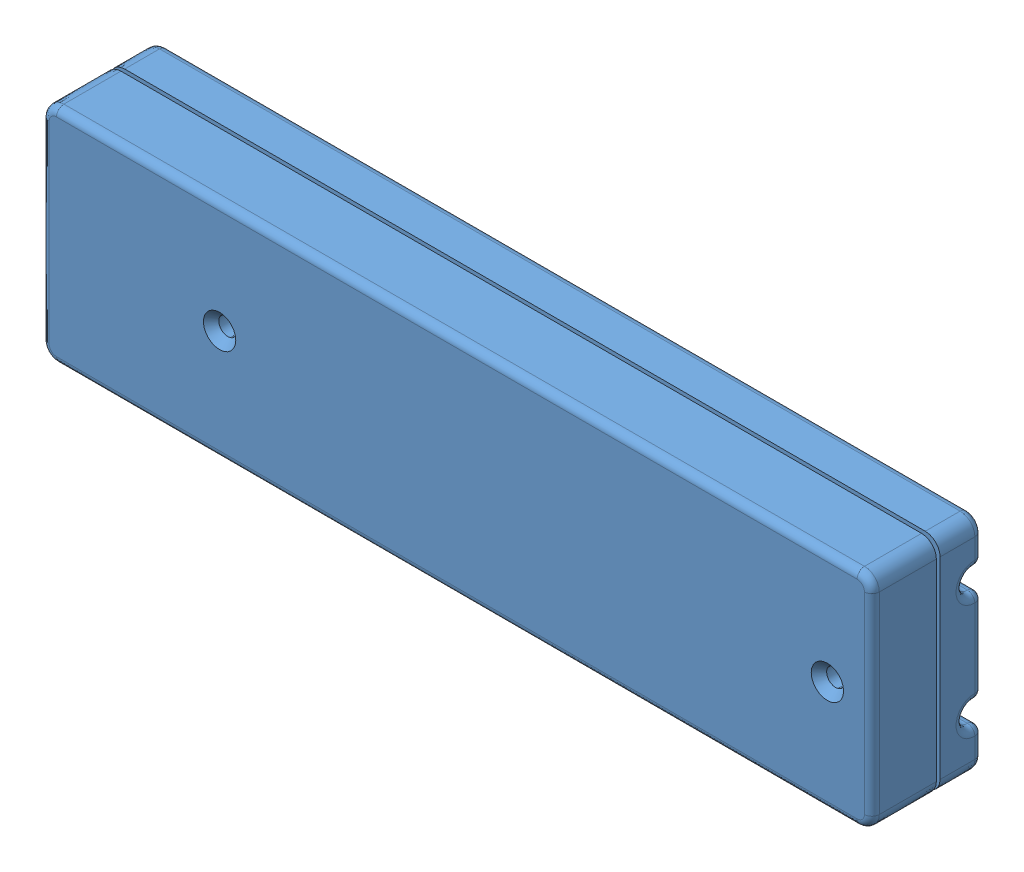
SolidWorks assembly two conector enclosure asm, configuration Default. Lengths in mm.
Overall size (112 30 15.6).
8 component instances, 5 part files, 10 mates.
Components (placement in the parent):
- two conector enclosure-1: two conector enclosure [Default] at origin size (112 30 14.9)
- two connector board asm-1: two connector board asm [Default] at origin size (108.78 25 10.13)
  - board-1: board [Default] at origin size (107 25 1.69)
  - Jack PCB-1: Jack PCB [Default] at (-45.55 -6.925 -3.2) x (-1 0 0) z (0 -1 0) size (19.05 7.4 7.9)
  - Jack PCB-2: Jack PCB [Default] at (-45.55 1.575 -3.2) x (-1 0 0) z (0 -1 0) size (19.05 7.4 7.9)
  - A79623-001-1: A79623-001 [Default] at (-50.96 9.2775 1.692) x (0 -1 0) z (-1 0 0) size (4.45 2.05 6.53)
- wire connector-3: wire connector [Default] at (-35.075 7.7801 0) x (1 0 0) z (0 1 0) size (86.5 9.6 7.28)
- wire connector-4: wire connector [Default] at (-35.075 -7.7801 0) x (1 0 0) z (0 1 0) size (86.5 9.6 7.28)
Mates (geometry in assembly coordinates):
- Coincident1: coordinate: point of ?
- Coincident5: coordinate: unknown of ?
- Coincident6: coincident anti-aligned: plane of two connector board asm-1/board-1 through (0 0 0) normal (0 0 -1); plane of ? through (52.7955 -4.7183 0) normal (0 0 1)
- Coincident7: coincident anti-aligned: plane of two connector board asm-1/board-1 through (0 0 0) normal (0 0 -1); plane of ? through (-37.8364 29.767 0) normal (0 0 1)
- Width2: width anti-aligned: plane of wire connector-3 through (51.425 7.7801 0) normal (1 0 0); plane of wire connector-3 through (-35.075 7.7801 0) normal (-1 0 0); plane of two conector enclosure-1 through (51.75 0 0) normal (-1 0 0); plane of two conector enclosure-1 through (-35.4 0 0) normal (1 0 0)
- Width3: width anti-aligned: plane of two conector enclosure-1 through (-35.4 4.507 0.0574) normal (0 0.999919 0.012741); plane of two conector enclosure-1 through (-35.4 11.0506 -0.1408) normal (0 -0.999919 0.012741); plane of wire connector-3 through (51.425 4.5301 -1.75) normal (0 -0.999919 -0.012738); plane of wire connector-3 through (51.425 10.93 -9.6) normal (0 0.999919 -0.012738)
- Coincident8: coincident anti-aligned: plane of two connector board asm-1/board-1 through (0 0 0) normal (0 0 -1); plane of wire connector-3 through (51.425 10.78 0) normal (0 0 1)
- Width4: width anti-aligned: plane of two conector enclosure-1 through (-35.4 -11.0506 -0.1408) normal (0 0.999919 0.012741); plane of two conector enclosure-1 through (-35.4 -4.507 0.0574) normal (0 -0.999919 0.012741); plane of wire connector-4 through (51.425 -11.03 -1.75) normal (0 -0.999919 -0.012738); plane of wire connector-4 through (51.425 -4.63 -9.6) normal (0 0.999919 -0.012738)
- Width5: width aligned: plane of wire connector-4 through (51.425 -7.7801 0) normal (1 0 0); plane of wire connector-4 through (-35.075 -7.7801 0) normal (-1 0 0); plane of two conector enclosure-1 through (-35.4 0 0) normal (1 0 0); plane of two conector enclosure-1 through (51.75 0 0) normal (-1 0 0)
- Coincident9: coincident anti-aligned: plane of two connector board asm-1/board-1 through (0 0 0) normal (0 0 -1); plane of wire connector-4 through (51.425 -4.7801 0) normal (0 0 1)
